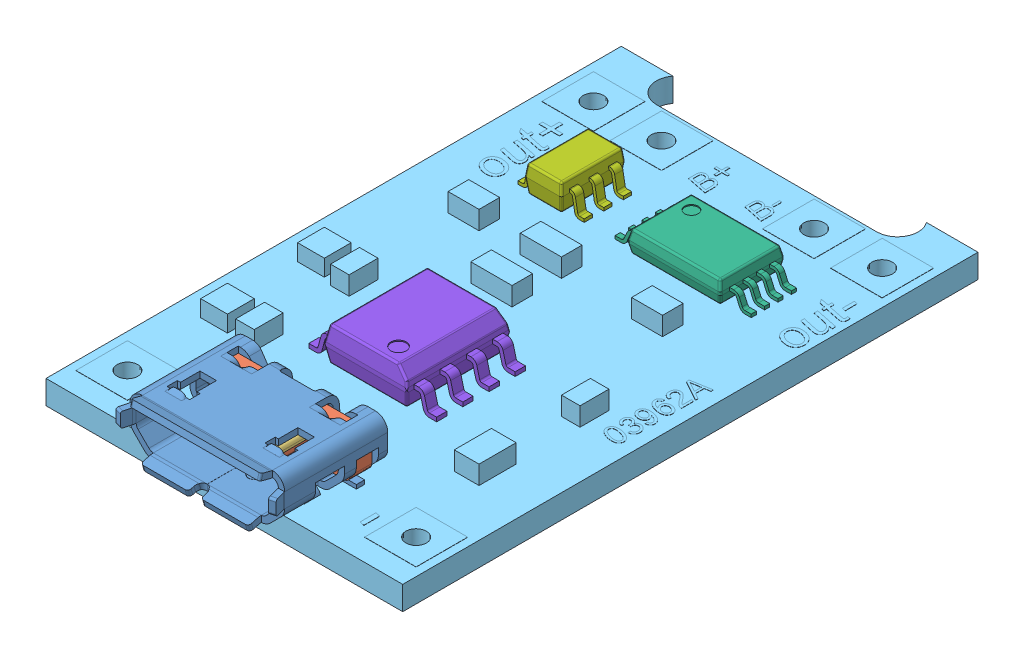
SolidWorks assembly TP4056(03962A), configuration По умолчанию. Lengths in mm.
Overall size (17.3 3.8 29.35).
13 component instances, 8 part files, 13 mates.
Components (placement in the parent):
- Копия micro_usb_connector^TP4056(03962A)-1: Копия micro_usb_connector^TP4056(03962A) [По умолчанию] at (4.4684 3.5679 3.8034) x (0 0 1) z (0 1 0) size (5.84 7.77 3.44) (virtual)
  - Копия shield^Копия micro_usb_connector_TP4056(03962A)-1: Копия shield^Копия micro_usb_connector_TP4056(03962A) [По умолчанию] at origin size (5.84 7.77 3.44) (virtual)
  - Копия socket_housing^Копия micro_usb_connector_TP4056(03962A)-1: Копия socket_housing^Копия micro_usb_connector_TP4056(03962A) [По умолчанию] at origin size (4.24 6.85 2.15) (virtual)
  - Копия socket_plate^Копия micro_usb_connector_TP4056(03962A)-1: Копия socket_plate^Копия micro_usb_connector_TP4056(03962A) [По умолчанию] at origin size (3.38 6.8 0.31) (virtual)
  - Копия terminal^Копия micro_usb_connector_TP4056(03962A)-2: Копия terminal^Копия micro_usb_connector_TP4056(03962A) [По умолчанию] at (0 -1.3 0) size (3.22 0.35 1.72) (virtual)
  - Копия terminal^Копия micro_usb_connector_TP4056(03962A)-6: Копия terminal^Копия micro_usb_connector_TP4056(03962A) [По умолчанию] at (0 -0.65 0) size (3.22 0.35 1.72) (virtual)
  - Копия terminal^Копия micro_usb_connector_TP4056(03962A)-7: Копия terminal^Копия micro_usb_connector_TP4056(03962A) [По умолчанию] at origin size (3.22 0.35 1.72) (virtual)
  - Копия terminal^Копия micro_usb_connector_TP4056(03962A)-8: Копия terminal^Копия micro_usb_connector_TP4056(03962A) [По умолчанию] at (0 0.65 0) size (3.22 0.35 1.72) (virtual)
  - Копия terminal^Копия micro_usb_connector_TP4056(03962A)-9: Копия terminal^Копия micro_usb_connector_TP4056(03962A) [По умолчанию] at (0 1.3 0) size (3.22 0.35 1.72) (virtual)
- Деталь11^TP4056(03962A)-1: Деталь11^TP4056(03962A) [По умолчанию] at (4.4684 3.5679 3.8034) x (0 0 1) z (0 1 0) size (27.9 17.3 2.06) (virtual)
- Копия MO-153AA^TP4056(03962A)-1: Копия MO-153AA^TP4056(03962A) [По умолчанию] at (7.0684 3.5679 -14.7726) x (0 0 1) z (0 1 0) size (3.1 6.6 1.2) (virtual)
- Копия SC-74^TP4056(03962A)-1: Копия SC-74^TP4056(03962A) [По умолчанию] at (0.7184 3.5679 -14.7726) x (0 0 -1) z (0 1 0) size (3.1 3.2 1.45) (virtual)
- Копия MS-012AA^TP4056(03962A)-1: Копия MS-012AA^TP4056(03962A) [По умолчанию] at (4.0184 3.5679 -3.8226) x (0 0 -1) z (0 1 0) size (5 6.2 1.75) (virtual)
Mates (geometry in assembly coordinates):
- На месте1: in place: plane of ? through (4.4684 3.5679 3.8034) normal (0 1 0); plane of ? through (4.4684 3.5679 3.8034) normal (0 1 0); moOrthogonalPlaneRef_w of ? through (4.4684 3.5679 3.8034) normal (0 1 0); unknown of ?; plane of ? through (4.4684 3.5679 3.8034) normal (0 1 0); unknown of ?; plane of ? through (4.4684 3.5679 3.8034) normal (0 1 0); unknown of ?
- Совпадение1: coincident aligned: plane of ?; plane of ?
- Совпадение2: coincident aligned: moOrthogonalPlaneRef_w of ?; plane of ?
- Совпадение3: coincident anti-aligned: moOrthogonalPlaneRef_w of ?; plane of ?
- Совпадение1: coincident anti-aligned: plane of Деталь11^TP4056(03962A)-1 through (4.4684 3.5679 3.8034) normal (0 1 0); plane of Копия MO-153AA^TP4056(03962A)-1 through (10.3684 3.5679 -13.6726) normal (0 -1 0)
- Расстояние1: distance = 4 mm aligned: plane of Копия MO-153AA^TP4056(03962A)-1 through (9.3184 4.1679 -16.3226) normal (0 0 -1); plane of Деталь11^TP4056(03962A)-1 through (4.4684 2.4179 -20.3226) normal (0 0 -1)
- Расстояние2: distance = 3.8 mm aligned: plane of Деталь11^TP4056(03962A)-1 through (13.1184 2.4179 3.8034) normal (1 0 0); plane of Копия MO-153AA^TP4056(03962A)-1 through (9.3184 4.1679 -13.2226) normal (1 0 0)
- Совпадение2: coincident anti-aligned: plane of Деталь11^TP4056(03962A)-1 through (4.4684 3.5679 3.8034) normal (0 1 0); plane of Копия SC-74^TP4056(03962A)-1 through (-0.6663 3.5679 -15.9226) normal (0 -1 0)
- Расстояние3: distance = 4 mm: plane of Деталь11^TP4056(03962A)-1 through (4.4684 2.4179 -20.3226) normal (0 0 -1); line of Копия SC-74^TP4056(03962A)-1 through (1.5192 4.4679 -16.3226) axis (-1 0 0)
- Расстояние4: distance = 4 mm: plane of Деталь11^TP4056(03962A)-1 through (-4.1816 2.4179 3.8034) normal (-1 0 0); line of Копия SC-74^TP4056(03962A)-1 through (-0.1816 4.4679 -16.2234) axis (0 0 1)
- Совпадение3: coincident anti-aligned: plane of Деталь11^TP4056(03962A)-1 through (4.4684 3.5679 3.8034) normal (0 1 0); plane of Копия MS-012AA^TP4056(03962A)-1 through (0.9184 3.5679 -2.1676) normal (0 -1 0)
- Расстояние5: distance = 6.2 mm aligned: plane of Копия MS-012AA^TP4056(03962A)-1 through (2.0184 4.3929 -6.3226) normal (-1 0 0); plane of Деталь11^TP4056(03962A)-1 through (-4.1816 2.4179 3.8034) normal (-1 0 0)
- Расстояние6: distance = 14 mm aligned: plane of Копия MS-012AA^TP4056(03962A)-1 through (6.0184 4.3929 -6.3226) normal (0 0 -1); plane of Деталь11^TP4056(03962A)-1 through (4.4684 2.4179 -20.3226) normal (0 0 -1)
